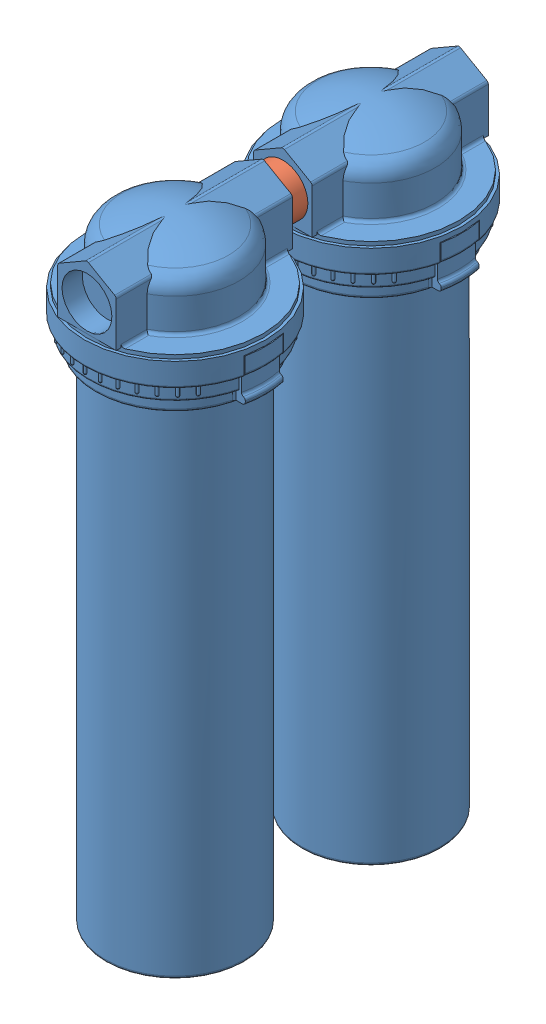
SolidWorks assembly ReadingTech_3P-150-M08-DC, configuration Default. Lengths in mm.
Overall size (121.86 436.11 252.73).
3 component instances, 2 part files, 3 mates.
Components (placement in the parent):
- ReadingTech_3P150M08F-1: ReadingTech_3P150M08F [Default] at (-24.209 -174.1067 -1.4291) size (121.86 436.11 121.67)
- ReadingTech_3P150M08F-2: ReadingTech_3P150M08F [Default] at (-24.209 -174.1067 -132.4931) size (121.86 436.11 121.67)
- ReadingTech- 90,150cfm_connector_1in-1: ReadingTech- 90,150cfm_connector_1in [Default] at (-24.209 214.8943 -60.3571) x (1 0 0) z (0 1 0) size (33.4 13.21 33.4)
Mates (geometry in assembly coordinates):
- Coincident1: coincident anti-aligned: circle of ReadingTech_3P150M08F-2; circle of ReadingTech- 90,150cfm_connector_1in-1
- Coincident2: coincident aligned: circle of ReadingTech_3P150M08F-1; circle of ReadingTech- 90,150cfm_connector_1in-1
- Coincident3: coincident aligned: plane of ReadingTech_3P150M08F-1 through (-4.651 227.5943 57.4989) normal (1 0 0); plane of ReadingTech_3P150M08F-2 through (-4.651 227.5943 -73.5651) normal (1 0 0)
